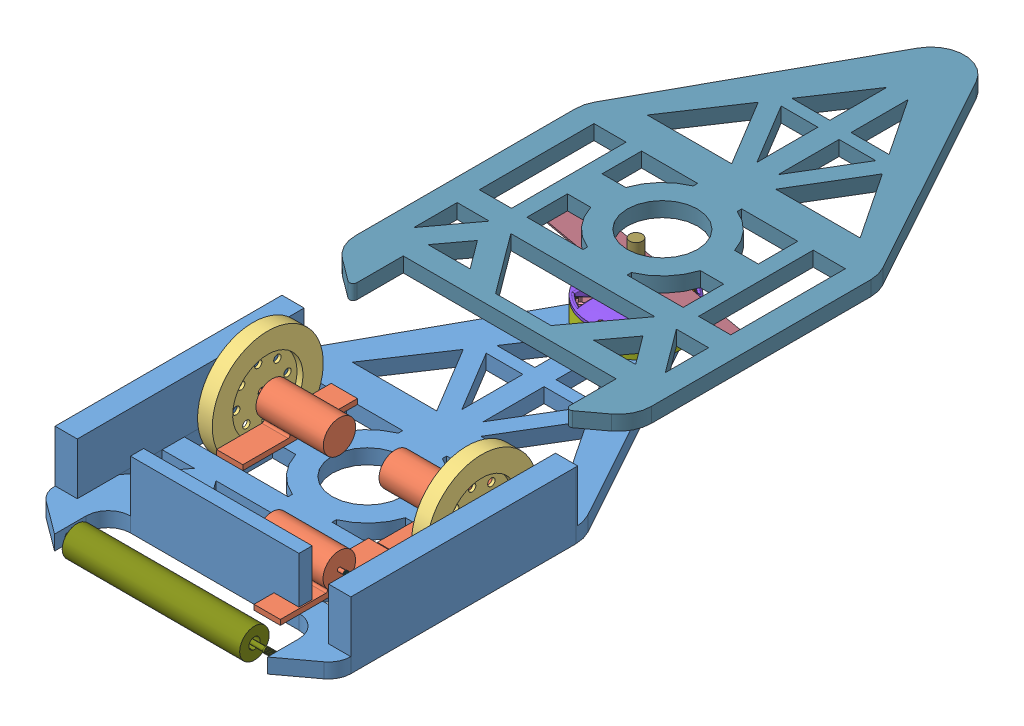
SolidWorks assembly bot, configuration Default. Lengths in mm.
Overall size (400 209.93 1088.92).
42 component instances, 16 part files, 21 mates.
Components (placement in the parent):
- Frame i-1: Frame i [Default] at (384.615 271.1754 784.6554) size (400 90 687.36)
- Motor-1: Motor [Default] at (166.3656 325.4482 581.9725) x (0 0.302284 0.953218) z (-1 0 0) size (149.86 72.12 109)
- wheel-1: wheel [Default] at (69.3656 319.1754 578.1994) x (0 -0.142299 0.989824) z (0 -0.989824 -0.142299) size (150 20 150)
- Motor-4: Motor [Default] at (241.7533 325.4482 574.4264) x (0 0.302284 -0.953218) z (1 0 0) size (149.86 72.12 109)
- wheel-3: wheel [Default] at (338.7533 319.1754 578.1994) x (0 -0.801449 0.598064) z (0 0.598064 0.801449) size (150 20 150)
- Assem2-1: Assem2 [Default] at (204.0595 291.1754 214.9257) x (0.307283 0 -0.951618) z (0 1 0) size (161.49 161.51 106)
  - Stator_1, solid-1: Stator_1, solid [Default] at (0 0 19.148) x (0.766044 0.642788 0) z (0 0 -1) size (114.57 114.7 22.1)
  - Bearing 303 ГОСТ 8338-75-1: Bearing 303 ГОСТ 8338-75 [По умолчанию] at (0 0 42.148) x (0 0 -1) z (0.852675 0.522442 0) size (14 47 47)
  - Bearing 303 ГОСТ 8338-75-2: Bearing 303 ГОСТ 8338-75 [По умолчанию] at (0 0 7) x (0 0 -1) z (0.643788 -0.765203 0) size (14 47 47)
  - Rotor-shaft holder-1: Rotor-shaft holder [Default] at (0 0 47.024) x (-0.273498 -0.961873 0) z (0 0 1) size (28 28 25)
  - rotor 1.3 cylinder-1: rotor 1.3 cylinder [Default] at (0 0 0.024) x (0 0 1) z (0.951715 0.306983 0) size (27 128 128)
  - rotor cap-1: rotor cap [Default] at (0 0 27.024) x (-0.273498 -0.961873 0) z (-0.961873 0.273498 0) size (128 24.12 128)
  - 25x14x2.5mm magnet-1: 25x14x2.5mm magnet [Default] at (-52.957 27.1257 12.524) x (0 0 1) z (0.890034 -0.455895 0) size (25 14 1.5)
  - 25x14x2.5mm magnet-2: 25x14x2.5mm magnet [Default] at (-38.5453 45.3267 12.524) x (0 0 1) z (0.647821 -0.761793 0) size (25 14 1.5)
  - 25x14x2.5mm magnet-3: 25x14x2.5mm magnet [Default] at (-18.2655 56.627 12.524) x (0 0 1) z (0.306983 -0.951715 0) size (25 14 1.5)
  - 25x14x2.5mm magnet-4: 25x14x2.5mm magnet [Default] at (4.7951 59.3065 12.524) x (0 0 1) z (-0.080591 -0.996747 0) size (25 14 1.5)
  - 25x14x2.5mm magnet-5: 25x14x2.5mm magnet [Default] at (27.1257 52.957 12.524) x (0 0 1) z (-0.455895 -0.890034 0) size (25 14 1.5)
  - 25x14x2.5mm magnet-6: 25x14x2.5mm magnet [Default] at (45.3267 38.5453 12.524) x (0 0 1) z (-0.761793 -0.647821 0) size (25 14 1.5)
  - 25x14x2.5mm magnet-7: 25x14x2.5mm magnet [Default] at (56.627 18.2655 12.524) x (0 0 1) z (-0.951715 -0.306983 0) size (25 14 1.5)
  - 25x14x2.5mm magnet-8: 25x14x2.5mm magnet [Default] at (59.3065 -4.7951 12.524) x (0 0 1) z (-0.996747 0.080591 0) size (25 14 1.5)
  - 25x14x2.5mm magnet-9: 25x14x2.5mm magnet [Default] at (52.957 -27.1257 12.524) x (0 0 1) z (-0.890034 0.455895 0) size (25 14 1.5)
  - 25x14x2.5mm magnet-10: 25x14x2.5mm magnet [Default] at (38.5453 -45.3267 12.524) x (0 0 1) z (-0.647821 0.761793 0) size (25 14 1.5)
  - 25x14x2.5mm magnet-11: 25x14x2.5mm magnet [Default] at (18.2655 -56.627 12.524) x (0 0 1) z (-0.306983 0.951715 0) size (25 14 1.5)
  - 25x14x2.5mm magnet-12: 25x14x2.5mm magnet [Default] at (-4.7951 -59.3065 12.524) x (0 0 1) z (0.080591 0.996747 0) size (25 14 1.5)
  - 25x14x2.5mm magnet-13: 25x14x2.5mm magnet [Default] at (-27.1257 -52.957 12.524) x (0 0 1) z (0.455895 0.890034 0) size (25 14 1.5)
  - 25x14x2.5mm magnet-14: 25x14x2.5mm magnet [Default] at (-45.3267 -38.5453 12.524) x (0 0 1) z (0.761793 0.647821 0) size (25 14 1.5)
  - 25x14x2.5mm magnet-15: 25x14x2.5mm magnet [Default] at (-56.627 -18.2655 12.524) x (0 0 1) z (0.951715 0.306983 0) size (25 14 1.5)
  - 25x14x2.5mm magnet-16: 25x14x2.5mm magnet [Default] at (-59.3065 4.7951 12.524) x (0 0 1) z (0.996747 -0.080591 0) size (25 14 1.5)
  - Bearing Hub holes-2: Bearing Hub holes [Default] at origin size (90 90 19.15)
  - Bold-1: Bold [Default] at (27.7128 -16 0) x (1 0 0) z (0 1 0) size (14 58 12.12)
  - Bold-2: Bold [Default] at (-27.7128 -16 0) x (-0.5 -0.866025 0) z (0.866025 -0.5 0) size (14 58 12.12)
  - Bold-3: Bold [Default] at (0 32 0) x (-0.5 0.866025 0) z (-0.866025 -0.5 0) size (14 58 12.12)
  - shaft-2: shaft [Default] x (0.273498 0.961873 0) z (0.961873 -0.273498 0) size (17 98 20)
  - Bold-7: Bold [3mm] at (53.7228 29.9354 39.0906) x (0 1 0) z (1 0 0) size (6.36 26.36 5.51)
  - Bold-8: Bold [3mm] at (29.9354 -53.7228 39.0906) x (1 0 0) z (0 -1 0) size (6.36 26.36 5.51)
  - Bold-9: Bold [3mm] at (-53.7228 -29.9354 39.0906) x (0 -1 0) z (-1 0 0) size (6.36 26.36 5.51)
  - Bold-10: Bold [3mm] at (-29.9354 53.7228 39.0906) x (-1 0 0) z (0 1 0) size (6.36 26.36 5.51)
- blade-2: blade [Default] at (159.9678 350.1754 191.758) x (0.984776 0 0.17383) z (-0.17383 0 0.984776) size (300 2 48.5)
- frame i 3-1: frame i 3 [Default] at (159.9185 361.1754 116.7576) x (1 0 0) z (0 1 0) size (400 682.42 20)
- Motor-5: Motor [Default] at (231.0039 325.4482 730.3618) x (0 0.302284 -0.953218) z (1 0 0) size (149.86 72.12 109)
- belt gear-1: belt gear [Default] at (330.0039 319.1754 734.1348) x (0 0.302284 -0.953218) z (1 0 0) size (6 5.98 10)
- drum-1: drum [Default] at (313.0039 281.1619 839.929) x (-1 0 0) z (0 0 1) size (302 40 40)
Mates (geometry in assembly coordinates):
- Concentric1: concentric anti-aligned: cylinder of Motor-1 through (57.3656 319.1754 578.1994) axis (1 0 0) radius 2.5251; cylinder of wheel-1 through (69.3656 319.1754 578.1994) axis (-1 0 0) radius 5
- Coincident1: coincident anti-aligned: plane of Frame i-1 through (384.615 291.1754 784.6554) normal (0 1 0); plane of Motor-1 through (166.3656 291.1754 581.9725) normal (0 -1 0)
- Coincident2: coincident aligned: plane of Motor-1 through (57.3656 319.1754 578.1994) normal (-1 0 0); plane of wheel-1 through (57.3656 319.1754 578.1994) normal (-1 0 0)
- Coincident3: coincident anti-aligned: line of Frame i-1 through (77.5689 291.1754 500.6994) axis (0 0 1); line of Motor-1 through (77.5689 291.1754 655.6994) axis (0 0 -1)
- Coincident6: coincident anti-aligned: line of Frame i-1 through (34.0892 291.1754 655.6994) axis (1 0 0); line of Motor-1 through (113.1388 291.1754 655.6994) axis (-1 0 0)
- Concentric2: concentric anti-aligned: cylinder of Motor-4 through (350.7533 319.1754 578.1994) axis (-1 0 0) radius 2.5251; cylinder of wheel-3 through (338.7533 319.1754 578.1994) axis (1 0 0) radius 5
- Coincident7: coincident aligned: plane of Motor-4 through (350.7533 319.1754 578.1994) normal (1 0 0); plane of wheel-3 through (350.7533 319.1754 578.1994) normal (1 0 0)
- Coincident8: coincident anti-aligned: plane of Frame i-1 through (384.615 291.1754 784.6554) normal (0 1 0); plane of Motor-4 through (241.7533 291.1754 574.4264) normal (0 -1 0)
- Coincident9: coincident aligned: line of Frame i-1 through (330.55 291.1754 500.6994) axis (0 0 1); line of Motor-4 through (330.55 291.1754 500.6994) axis (0 0 1)
- Coincident10: coincident anti-aligned: line of Frame i-1 through (330.55 291.1754 655.6994) axis (1 0 0); line of Motor-4 through (330.55 291.1754 655.6994) axis (-1 0 0)
- Coincident11: coincident anti-aligned: plane of Frame i-1 through (384.615 291.1754 784.6554) normal (0 1 0); plane of Assem2-1/shaft-2 through (204.0595 291.1754 214.9257) normal (0 -1 0)
- Coincident15: coincident anti-aligned: cylinder of Frame i-1 through (204.0595 291.1754 214.9257) axis (0 -1 0) radius 45; circle of Assem2-1/Bearing Hub holes-2
- Concentric7: concentric aligned: circle of Assem2-1/Rotor-shaft holder-1; cylinder of blade-2 through (204.0595 350.1754 214.9257) axis (0 1 0) radius 7.5
- Coincident36: coincident anti-aligned: plane of Frame i-1 through (384.615 361.1754 784.6554) normal (0 1 0); plane of frame i 3-1 through (159.9185 361.1754 116.7576) normal (0 -1 0)
- Coincident37: coincident aligned: line of Frame i-1 through (4.0595 361.1754 496.2323) axis (0 0 1); line of frame i 3-1 through (4.0595 361.1754 97.312) axis (0 0 1)
- Concentric8: concentric anti-aligned: cylinder of Motor-5 through (340.0039 319.1754 734.1348) axis (-1 0 0) radius 2.5251; cylinder of belt gear-1 through (330.0039 319.1754 734.1348) axis (1 0 0) radius 2.55
- Coincident38: coincident aligned: plane of Motor-5 through (340.0039 319.1754 734.1348) normal (1 0 0); plane of belt gear-1 through (340.0039 320.6661 733.9675) normal (1 0 0)
- Coincident39: coincident anti-aligned: plane of Frame i-1 through (384.615 291.1754 784.6554) normal (0 1 0); plane of Motor-5 through (231.0039 291.1754 730.3618) normal (0 -1 0)
- Coincident41: coincident anti-aligned: plane of Frame i-1 through (348.0039 291.1754 784.6554) normal (-1 0 0); plane of drum-1 through (348.0039 281.1619 839.929) normal (1 0 0)
- Coincident42: coincident aligned: plane of Motor-5 through (340.0039 319.1754 734.1348) normal (1 0 0); plane of drum-1 through (340.0039 281.1619 839.929) normal (1 0 0)
- Distance1: distance = 37 mm aligned: plane of blade-2 through (159.9678 352.1754 191.758) normal (0 1 0); plane of Assem2-1/shaft-2 through (204.0595 389.1754 214.9257) normal (0 1 0)
